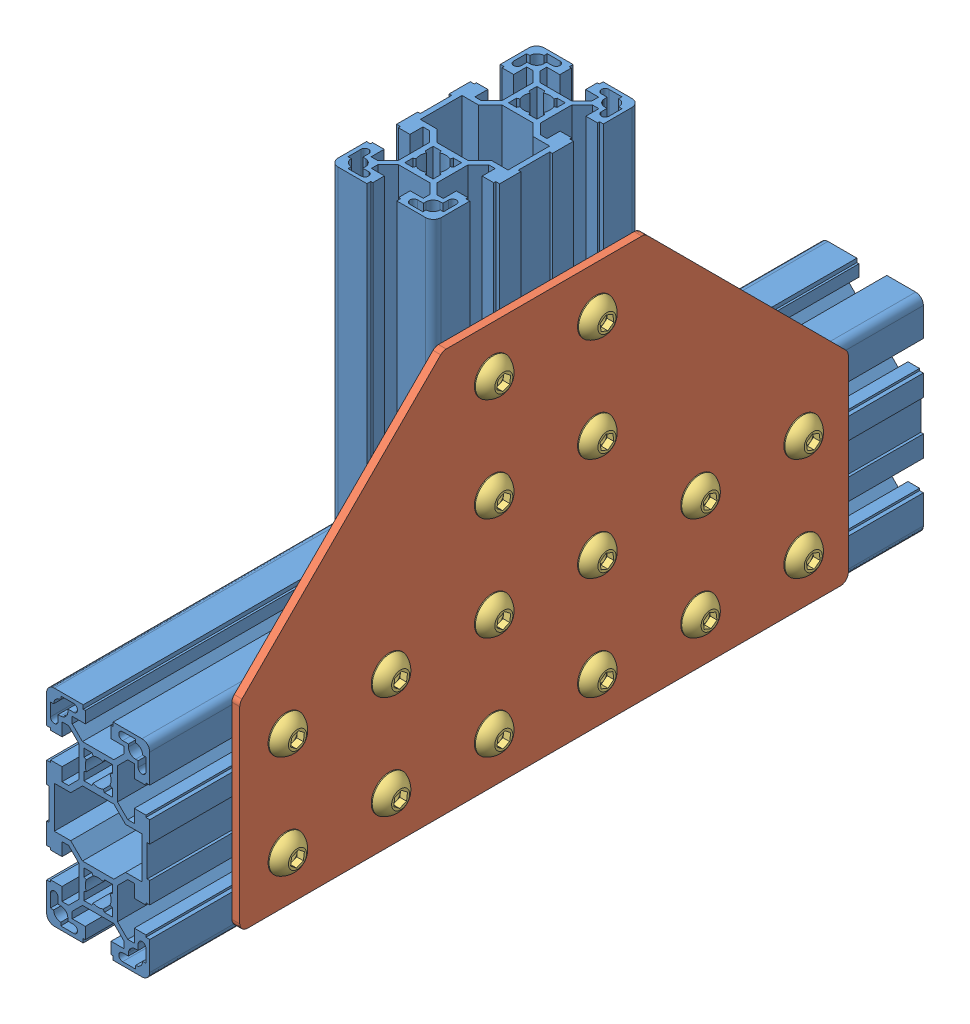
SolidWorks assembly Сборка AL-T40.160240 Т-соединитель 160х240, 40 серия, configuration По умолчанию. Lengths in mm.
Overall size (47.4 200 300).
20 component instances, 3 part files, 23 mates.
Components (placement in the parent):
- AL-PS-4080-1: AL-PS-4080 [Default] at origin size (40 80 300)
- AL-PS-4080-2: AL-PS-4080 [-01] at (0 40 -150) x (1 0 0) z (0 -1 0) size (40 80 120)
- AL-T40.160240 Т-соединитель 160х240, 40 серия-1: AL-T40.160240 Т-соединитель 160х240, 40 серия [По умолчанию] at (23.9913 41.4125 -150.8616) x (0 0 -1) z (0 1 0) size (236 3 156)
- Винт ISO 7380 - M8 x 16-1: Винт ISO 7380 - M8 x 16 [По умолчанию] at (27.4 19.8916 -49.8916) x (-1 0 0) z (0 0.924225 0.381849) size (20.4 14 14)
- Винт ISO 7380 - M8 x 16-2: Винт ISO 7380 - M8 x 16 [По умолчанию] at (27.4 -20.1084 -49.8916) x (-1 0 0) z (0 0.924225 0.381849) size (20.4 14 14)
- Винт ISO 7380 - M8 x 16-3: Винт ISO 7380 - M8 x 16 [По умолчанию] at (27.4 19.8916 -89.8916) x (-1 0 0) z (0 0.924225 0.381849) size (20.4 14 14)
- Винт ISO 7380 - M8 x 16-4: Винт ISO 7380 - M8 x 16 [По умолчанию] at (27.4 -20.1084 -89.8916) x (-1 0 0) z (0 0.924225 0.381849) size (20.4 14 14)
- Винт ISO 7380 - M8 x 16-5: Винт ISO 7380 - M8 x 16 [По умолчанию] at (27.4 -20.1084 -129.8916) x (-1 0 0) z (0 0.924225 0.381849) size (20.4 14 14)
- Винт ISO 7380 - M8 x 16-6: Винт ISO 7380 - M8 x 16 [По умолчанию] at (27.4 19.8916 -129.8916) x (-1 0 0) z (0 0.924225 0.381849) size (20.4 14 14)
- Винт ISO 7380 - M8 x 16-7: Винт ISO 7380 - M8 x 16 [По умолчанию] at (27.4 59.8916 -129.8916) x (-1 0 0) z (0 0.924225 0.381849) size (20.4 14 14)
- Винт ISO 7380 - M8 x 16-8: Винт ISO 7380 - M8 x 16 [По умолчанию] at (27.4 99.8916 -129.8916) x (-1 0 0) z (0 0.924225 0.381849) size (20.4 14 14)
- Винт ISO 7380 - M8 x 16-9: Винт ISO 7380 - M8 x 16 [По умолчанию] at (-3.4134 93.1706 -155.4276) size (20.4 14 14)
- Винт ISO 7380 - M8 x 16-10: Винт ISO 7380 - M8 x 16 [По умолчанию] at (27.4 19.8916 -209.8916) x (-1 0 0) z (0 -0.924225 0.381849) size (20.4 14 14)
- Винт ISO 7380 - M8 x 16-11: Винт ISO 7380 - M8 x 16 [По умолчанию] at (27.4 19.8916 -249.8916) x (-1 0 0) z (0 -0.924225 0.381849) size (20.4 14 14)
- Винт ISO 7380 - M8 x 16-12: Винт ISO 7380 - M8 x 16 [По умолчанию] at (27.4 -20.1084 -249.8916) x (-1 0 0) z (0 -0.924225 0.381849) size (20.4 14 14)
- Винт ISO 7380 - M8 x 16-13: Винт ISO 7380 - M8 x 16 [По умолчанию] at (27.4 59.8916 -169.8916) x (-1 0 0) z (0 -0.924225 0.381849) size (20.4 14 14)
- Винт ISO 7380 - M8 x 16-14: Винт ISO 7380 - M8 x 16 [По умолчанию] at (27.4 99.8916 -169.8916) x (-1 0 0) z (0 -0.924225 0.381849) size (20.4 14 14)
- Винт ISO 7380 - M8 x 16-15: Винт ISO 7380 - M8 x 16 [По умолчанию] at (27.4 -20.1084 -209.8916) x (-1 0 0) z (0 -0.924225 0.381849) size (20.4 14 14)
- Винт ISO 7380 - M8 x 16-16: Винт ISO 7380 - M8 x 16 [По умолчанию] at (27.4 19.8916 -169.8916) x (-1 0 0) z (0 -0.924225 0.381849) size (20.4 14 14)
- Винт ISO 7380 - M8 x 16-17: Винт ISO 7380 - M8 x 16 [По умолчанию] at (27.4 -20.1084 -169.8916) x (-1 0 0) z (0 -0.924225 0.381849) size (20.4 14 14)
Mates (geometry in assembly coordinates):
- Совпадение1: coincident aligned: plane of AL-PS-4080-1 through (20 25.9084 -300) normal (1 0 0); plane of AL-PS-4080-2 through (20 160 -124.0916) normal (1 0 0)
- Совпадение2: coincident anti-aligned: plane of AL-PS-4080-1 through (17 40 -300) normal (0 1 0); plane of AL-PS-4080-2 through (-17 40 -187) normal (0 -1 0)
- Ширина1: width anti-aligned: plane of AL-PS-4080-2 through (17 160 -110) normal (0 0 1); plane of AL-PS-4080-2 through (17 160 -190) normal (0 0 -1); plane of AL-PS-4080-1 through (-17 -37 -300) normal (0 0 -1); plane of AL-PS-4080-1 through (-17 -37 0) normal (0 0 1)
- Совпадение3: coincident anti-aligned: plane of AL-PS-4080-1 through (20 25.9084 -300) normal (1 0 0); plane of AL-T40.160240 Т-соединитель 160х240, 40 серия-1 through (20 114.8916 -187.8205) normal (-1 0 0)
- Ширина2: width: plane of AL-PS-4080-1 through (14 -25.1084 -300) normal (0 1 0); plane of AL-PS-4080-1 through (18.5 -15.1084 -300) normal (0 -1 0); cylinder of AL-T40.160240 Т-соединитель 160х240, 40 серия-1 through (20 -20.1084 -49.8916) axis (1 0 0) radius 4.1
- Ширина3: width: plane of AL-PS-4080-1 through (14 -25.1084 -300) normal (0 1 0); plane of AL-PS-4080-1 through (18.5 -15.1084 -300) normal (0 -1 0); cylinder of AL-T40.160240 Т-соединитель 160х240, 40 серия-1 through (20 -20.1084 -249.8916) axis (1 0 0) radius 4.1
- Ширина4: width: plane of AL-PS-4080-2 through (14 160 -124.8916) normal (0 0 -1); plane of AL-PS-4080-2 through (18.5 160 -134.8916) normal (0 0 1); cylinder of AL-T40.160240 Т-соединитель 160х240, 40 серия-1 through (20 99.8916 -129.8916) axis (1 0 0) radius 4.1
- Концентричный11: concentric aligned: cylinder of AL-T40.160240 Т-соединитель 160х240, 40 серия-1 through (20 19.8916 -49.8916) axis (1 0 0) radius 4.1; cylinder of Винт ISO 7380 - M8 x 16-1 through (23 19.8916 -49.8916) axis (1 0 0) radius 7
- Совпадение41: coincident anti-aligned: plane of AL-T40.160240 Т-соединитель 160х240, 40 серия-1 through (23 114.8916 -187.8205) normal (1 0 0); plane of Винт ISO 7380 - M8 x 16-1 through (23 17.2186 -43.422) normal (-1 0 0)
- Концентричный21: concentric aligned: cylinder of AL-T40.160240 Т-соединитель 160х240, 40 серия-1 through (20 -20.1084 -49.8916) axis (1 0 0) radius 4.1; cylinder of Винт ISO 7380 - M8 x 16-2 through (23 -20.1084 -49.8916) axis (1 0 0) radius 7
- Совпадение51: coincident anti-aligned: plane of AL-T40.160240 Т-соединитель 160х240, 40 серия-1 through (23 114.8916 -187.8205) normal (1 0 0); plane of Винт ISO 7380 - M8 x 16-2 through (23 -22.7814 -43.422) normal (-1 0 0)
- Концентричный31: concentric aligned: cylinder of AL-T40.160240 Т-соединитель 160х240, 40 серия-1 through (20 19.8916 -89.8916) axis (1 0 0) radius 4.1; cylinder of Винт ISO 7380 - M8 x 16-3 through (23 19.8916 -89.8916) axis (1 0 0) radius 7
- Совпадение61: coincident anti-aligned: plane of AL-T40.160240 Т-соединитель 160х240, 40 серия-1 through (23 114.8916 -187.8205) normal (1 0 0); plane of Винт ISO 7380 - M8 x 16-3 through (23 17.2186 -83.422) normal (-1 0 0)
- Концентричный41: concentric aligned: cylinder of AL-T40.160240 Т-соединитель 160х240, 40 серия-1 through (20 -20.1084 -89.8916) axis (1 0 0) radius 4.1; cylinder of Винт ISO 7380 - M8 x 16-4 through (23 -20.1084 -89.8916) axis (1 0 0) radius 7
- Совпадение71: coincident anti-aligned: plane of AL-T40.160240 Т-соединитель 160х240, 40 серия-1 through (23 114.8916 -187.8205) normal (1 0 0); plane of Винт ISO 7380 - M8 x 16-4 through (23 -22.7814 -83.422) normal (-1 0 0)
- Концентричный51: concentric aligned: cylinder of AL-T40.160240 Т-соединитель 160х240, 40 серия-1 through (20 -20.1084 -129.8916) axis (1 0 0) radius 4.1; cylinder of Винт ISO 7380 - M8 x 16-5 through (23 -20.1084 -129.8916) axis (1 0 0) radius 7
- Совпадение81: coincident anti-aligned: plane of AL-T40.160240 Т-соединитель 160х240, 40 серия-1 through (23 114.8916 -187.8205) normal (1 0 0); plane of Винт ISO 7380 - M8 x 16-5 through (23 -22.7814 -123.422) normal (-1 0 0)
- Концентричный61: concentric aligned: cylinder of AL-T40.160240 Т-соединитель 160х240, 40 серия-1 through (20 19.8916 -129.8916) axis (1 0 0) radius 4.1; cylinder of Винт ISO 7380 - M8 x 16-6 through (23 19.8916 -129.8916) axis (1 0 0) radius 7
- Совпадение91: coincident anti-aligned: plane of AL-T40.160240 Т-соединитель 160х240, 40 серия-1 through (23 114.8916 -187.8205) normal (1 0 0); plane of Винт ISO 7380 - M8 x 16-6 through (23 17.2186 -123.422) normal (-1 0 0)
- Концентричный71: concentric aligned: cylinder of AL-T40.160240 Т-соединитель 160х240, 40 серия-1 through (20 59.8916 -129.8916) axis (1 0 0) radius 4.1; cylinder of Винт ISO 7380 - M8 x 16-7 through (23 59.8916 -129.8916) axis (1 0 0) radius 7
- Совпадение101: coincident anti-aligned: plane of AL-T40.160240 Т-соединитель 160х240, 40 серия-1 through (23 114.8916 -187.8205) normal (1 0 0); plane of Винт ISO 7380 - M8 x 16-7 through (23 57.2186 -123.422) normal (-1 0 0)
- Концентричный81: concentric aligned: cylinder of AL-T40.160240 Т-соединитель 160х240, 40 серия-1 through (20 99.8916 -129.8916) axis (1 0 0) radius 4.1; cylinder of Винт ISO 7380 - M8 x 16-8 through (23 99.8916 -129.8916) axis (1 0 0) radius 7
- Совпадение111: coincident anti-aligned: plane of AL-T40.160240 Т-соединитель 160х240, 40 серия-1 through (23 114.8916 -187.8205) normal (1 0 0); plane of Винт ISO 7380 - M8 x 16-8 through (23 97.2186 -123.422) normal (-1 0 0)
